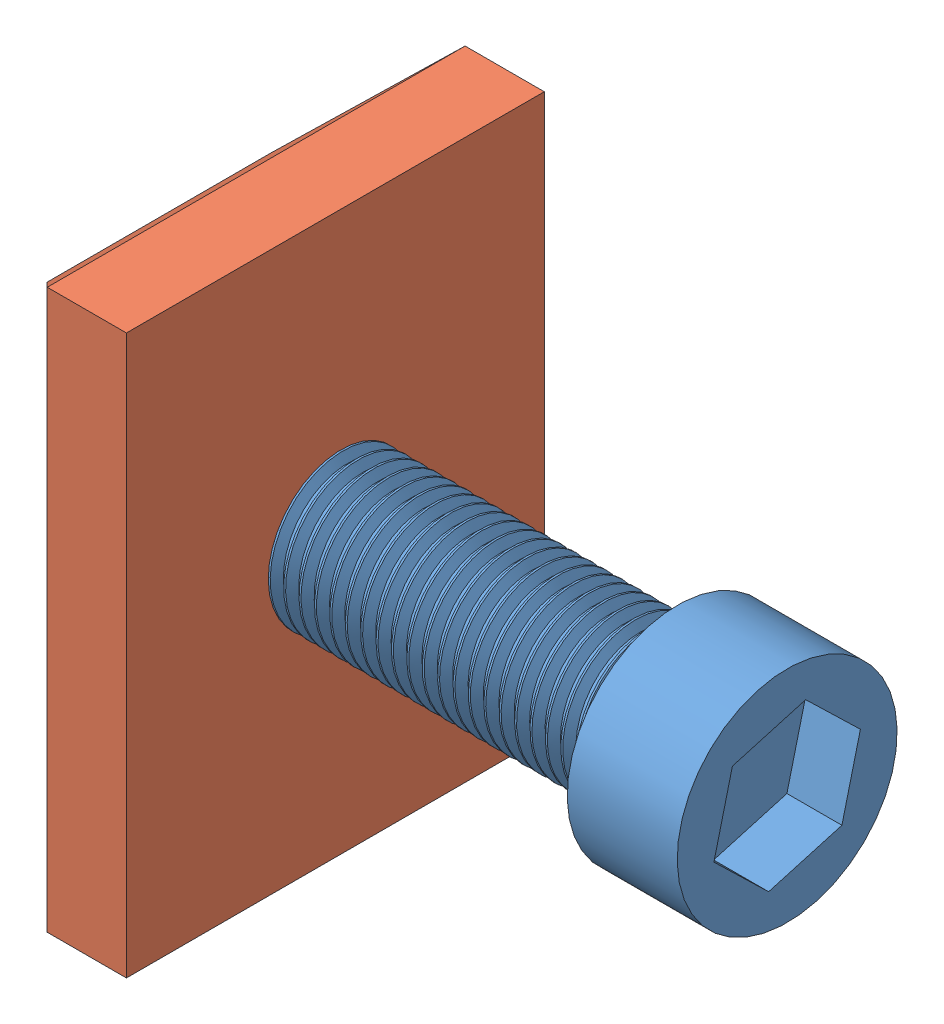
SolidWorks assembly M3 nut and bolt, configuration Default. Lengths in mm.
Overall size (14.41 12.7 9.5).
2 component instances, 2 part files, 1 mates.
Components (placement in the parent):
- M3 bolt-1: M3 bolt [Default] at (-0.6384 10.9956 20.1498) x (0 -0.96156 -0.274595) z (-1 0 0) size (5 5 12.17)
- M3 T-nut-1: M3 T-nut [Default] at (-9.66 10.9956 20.1498) size (4.28 12.7 9.5)
Mates (geometry in assembly coordinates):
- Coincident2: coincident: axis of M3 bolt-1 through (-1.8884 10.9956 20.1498) axis (1 0 0); axis of M3 T-nut-1 through (-13.6671 10.9956 20.1498) axis (1 0 0)
